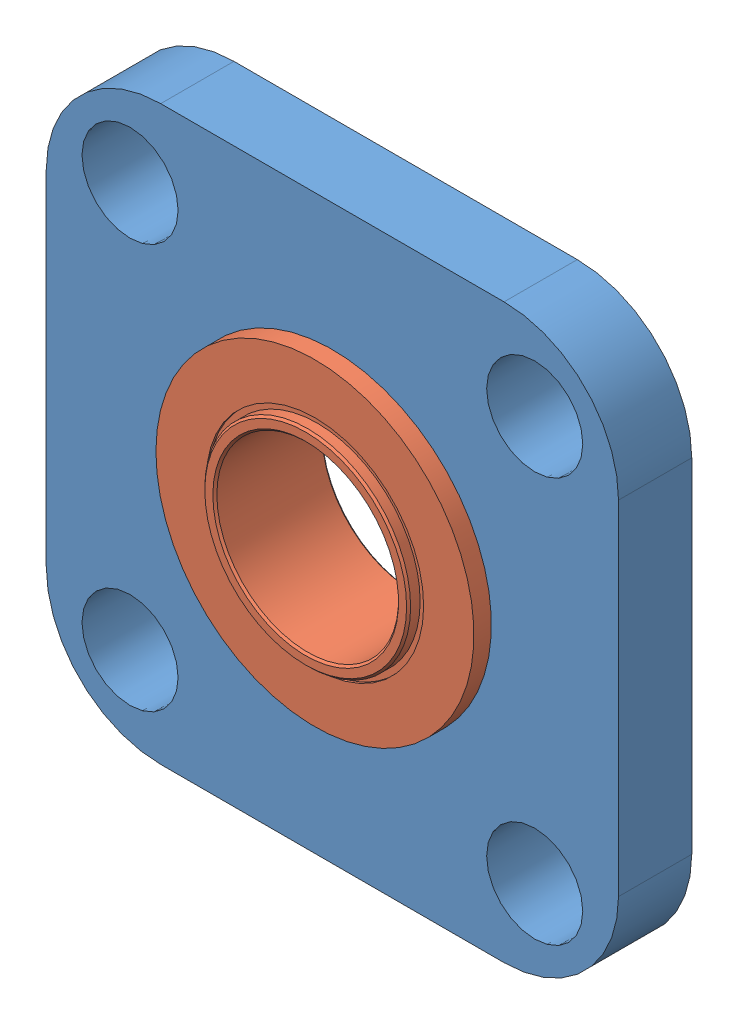
SolidWorks assembly bearing mount, configuration Default. Lengths in mm.
Overall size (25 25 4.78).
2 component instances, 2 part files, 2 mates.
Components (placement in the parent):
- bearing mount 1-1: bearing mount 1 [Default] at (21.4691 -34.8101 44.4794) x (-1 0 0) z (0 0 -1) size (25 25 3.2)
- 57155K338_STAINLESS STEEL BALL BEARING-2: 57155K338_STAINLESS STEEL BALL BEARING [57155K338] at (21.4691 -34.8101 43.257) x (0.999994 -0.003494 0) z (0 0 -1) size (13.89 13.89 4.78)
Mates (geometry in assembly coordinates):
- Concentric8: concentric anti-aligned: cylinder of bearing mount 1-1 through (21.4691 -34.8101 44.4804) axis (0 0 -1) radius 6.32; circle of 57155K338_STAINLESS STEEL BALL BEARING-2
- Coincident13: coincident anti-aligned: plane of bearing mount 1-1 through (21.4691 -34.8101 44.4794) normal (0 0 1); plane of 57155K338_STAINLESS STEEL BALL BEARING-2 through (21.4525 -39.5599 44.4794) normal (0 0 -1)
